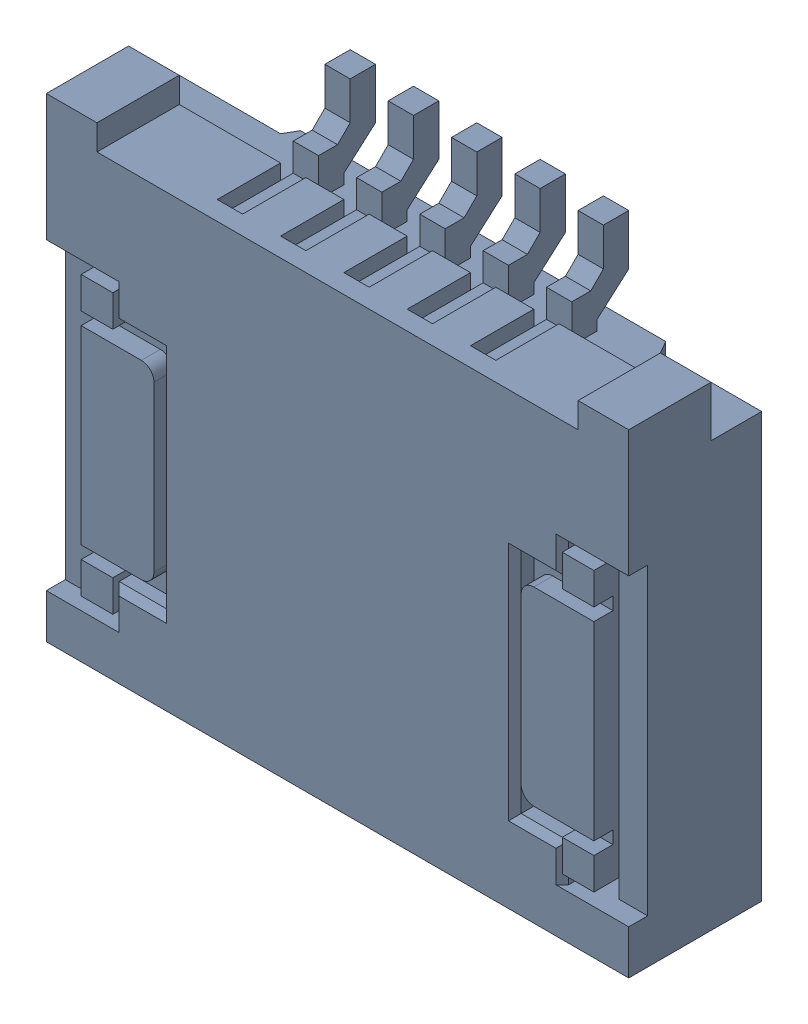
SolidWorks assembly J5.step, configuration Default. Lengths in mm.
Overall size (4.6 4.05 1.2).
2 component instances, 1 part files, 0 mates.
Components (placement in the parent):
- 512810594.step-1: 512810594.step [Default] at (124.6977 -22.5218 0.05) x (1 0 0) z (0 -1 0) size (4.6 1.2 4.05)
  - Open CASCADE STEP translator 7.5 1.170.1.1.step-1: Open CASCADE STEP translator 7.5 1.170.1.1.step [Default] at origin size (4.6 1.2 4.05)
